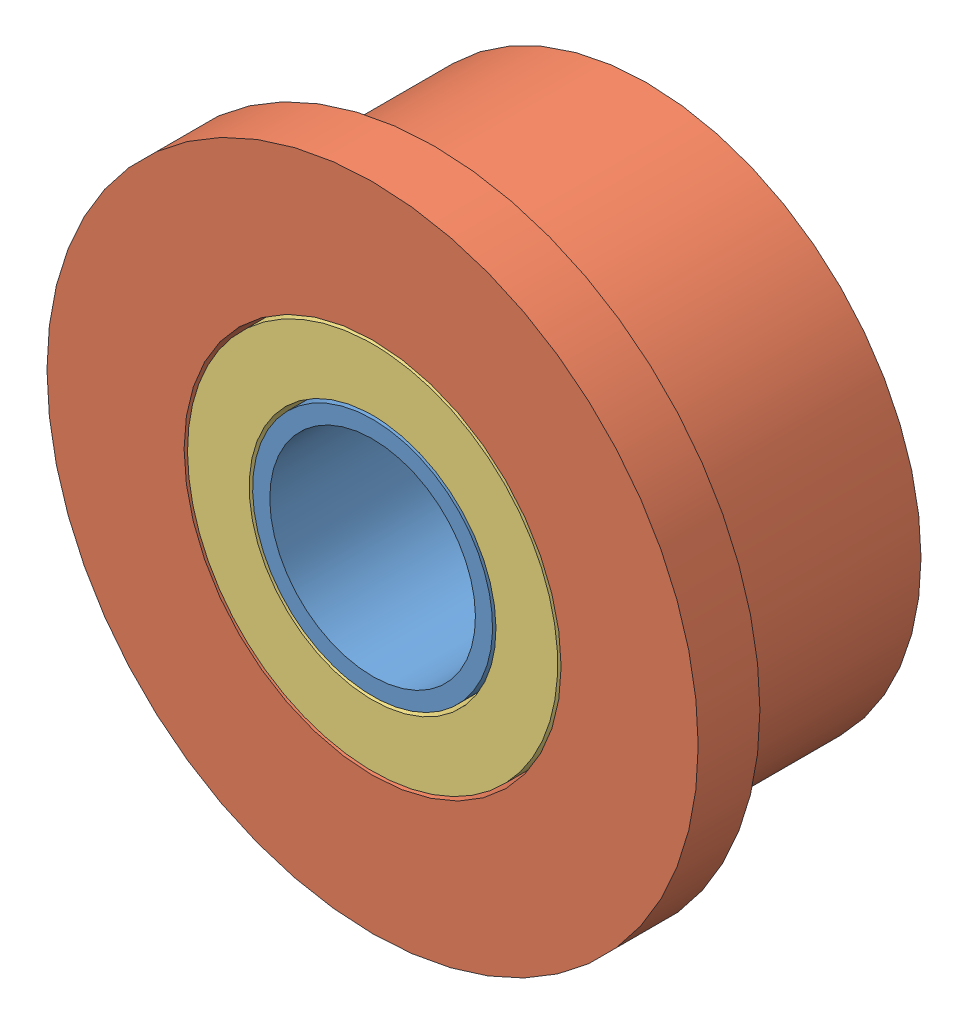
SolidWorks assembly 法兰轴承, configuration 默认. Lengths in mm.
Overall size (9.5 9.5 4).
4 component instances, 3 part files, 6 mates.
Components (placement in the parent):
- 法兰轴承内-1: 法兰轴承内 [默认] at (-0.1591 0.5058 2) x (-0.26947 -0.963009 0) z (0 0 1) size (3.5 3.5 4)
- 法兰轴承外-1: 法兰轴承外 [默认] at (-0.1591 0.5058 2) size (9.5 9.5 4)
- 法兰轴承盖-1: 法兰轴承盖 [默认] at (-0.1591 0.5058 5) x (0.025092 0.999685 0) z (0 0 1) size (5.4 5.4 1)
- 法兰轴承盖-2: 法兰轴承盖 [默认] at (-0.1591 0.5058 2) size (5.4 5.4 1)
Mates (geometry in assembly coordinates):
- 同心1: concentric: circle of 法兰轴承内-1; circle of 法兰轴承外-1
- 重合1: coincident: plane of 法兰轴承内-1 through (-0.1591 0.5058 6) normal (0 0 1); plane of 法兰轴承外-1 through (-0.1591 0.5058 6) normal (0 0 1)
- 重合2: coincident: plane of 法兰轴承外-1 through (-0.1591 0.5058 6) normal (0 0 1); plane of 法兰轴承盖-1 through (-0.1591 0.5058 6) normal (0 0 1)
- 同心2: concentric: circle of 法兰轴承外-1; circle of 法兰轴承盖-1
- 重合4: coincident: plane of 法兰轴承外-1 through (-0.1591 0.5058 2) normal (0 0 -1); plane of 法兰轴承盖-2 through (-0.1591 0.5058 2) normal (0 0 -1)
- 同心3: concentric: circle of 法兰轴承外-1; circle of 法兰轴承盖-2
